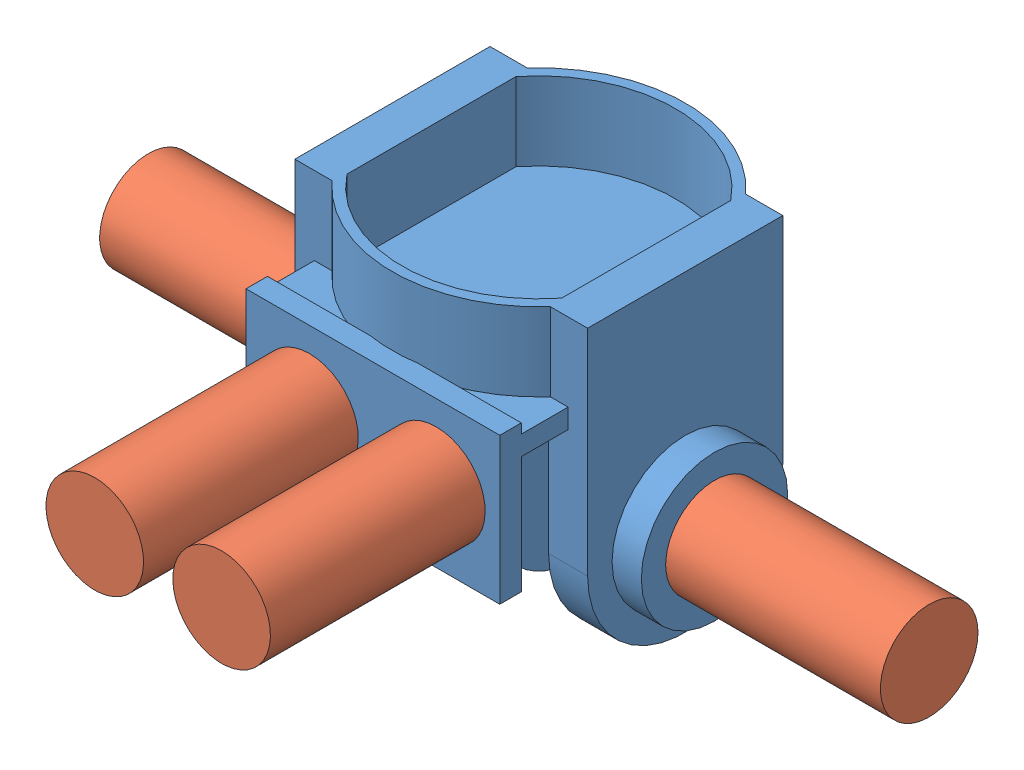
SolidWorks assembly J1wMotors, configuration Default. Lengths in mm.
Overall size (400 160 270).
5 component instances, 2 part files, 8 mates.
Components (placement in the parent):
- J1-1: J1 [Default] at (79.4739 128.2435 123.755) size (180 160 160)
- motor-1: motor [Default] at (-10.5261 68.2435 123.755) x (0 1 0) z (0 0 1) size (50 110 50)
- motor-2: motor [Default] at (46.9739 105.7435 208.755) x (1 0 0) z (0 -1 0) size (50 110 50)
- motor-3: motor [Default] at (111.9739 105.7435 208.755) x (1 0 0) z (0 -1 0) size (50 110 50)
- motor-4: motor [Default] at (279.4739 68.2435 123.755) x (0 1 0) z (0 0 1) size (50 110 50)
Mates (geometry in assembly coordinates):
- Coincident1: coincident anti-aligned: plane of J1-1 through (-10.5261 68.2435 123.755) normal (-1 0 0); plane of motor-1 through (-10.5261 68.2435 123.755) normal (1 0 0)
- Concentric2: concentric aligned: circle of J1-1; circle of motor-1
- Coincident2: coincident anti-aligned: plane of J1-1 through (169.4739 68.2435 123.755) normal (1 0 0); plane of motor-4 through (169.4739 68.2435 123.755) normal (-1 0 0)
- Concentric3: concentric anti-aligned: circle of J1-1; circle of motor-4
- Coincident3: coincident anti-aligned: plane of J1-1 through (79.4739 128.2435 208.755) normal (0 0 1); plane of motor-2 through (46.9739 105.7435 208.755) normal (0 0 -1)
- Coincident4: coincident anti-aligned: plane of J1-1 through (79.4739 128.2435 208.755) normal (0 0 1); plane of motor-3 through (111.9739 105.7435 208.755) normal (0 0 -1)
- Concentric4: concentric aligned: circle of motor-3; circle of assembly
- Concentric5: concentric aligned: circle of motor-2; circle of assembly
